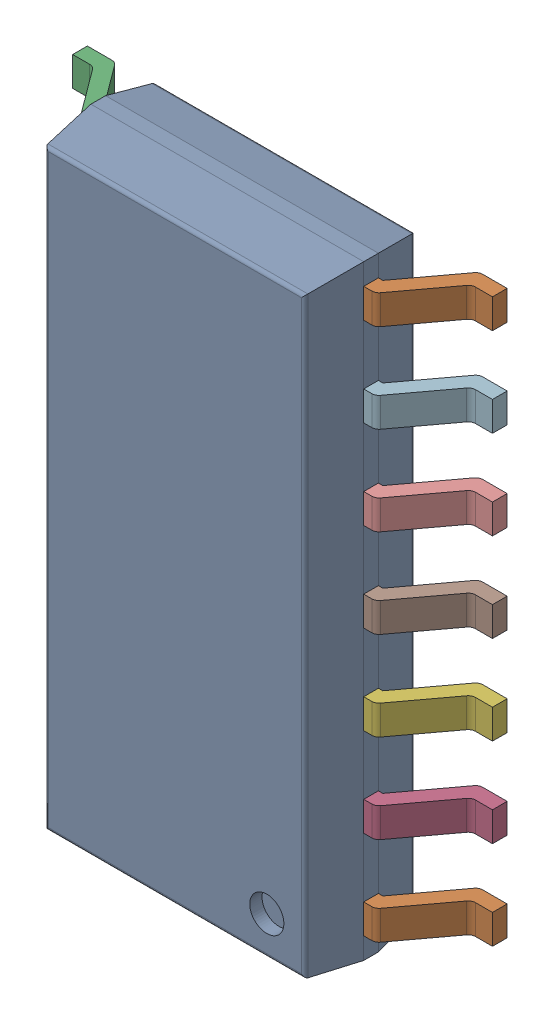
SolidWorks assembly IC11_IC101_1.step, configuration Default. Lengths in mm.
Overall size (6 8.65 1.75).
3 component instances, 2 part files, 0 mates.
Components (placement in the parent):
- 6348793888_1.step-3: 6348793888_1.step [Default] at (487.749 291.435 0) x (-1 0 0) z (0 0 1) size (6 8.65 1.75)
  - Body-16_1.step-14: Body-16_1.step [Default] at origin size (3.9 8.65 1.57)
  - PinsArrayLR-17_1.step-14: PinsArrayLR-17_1.step [Default] at origin size (6 8.04 1)
